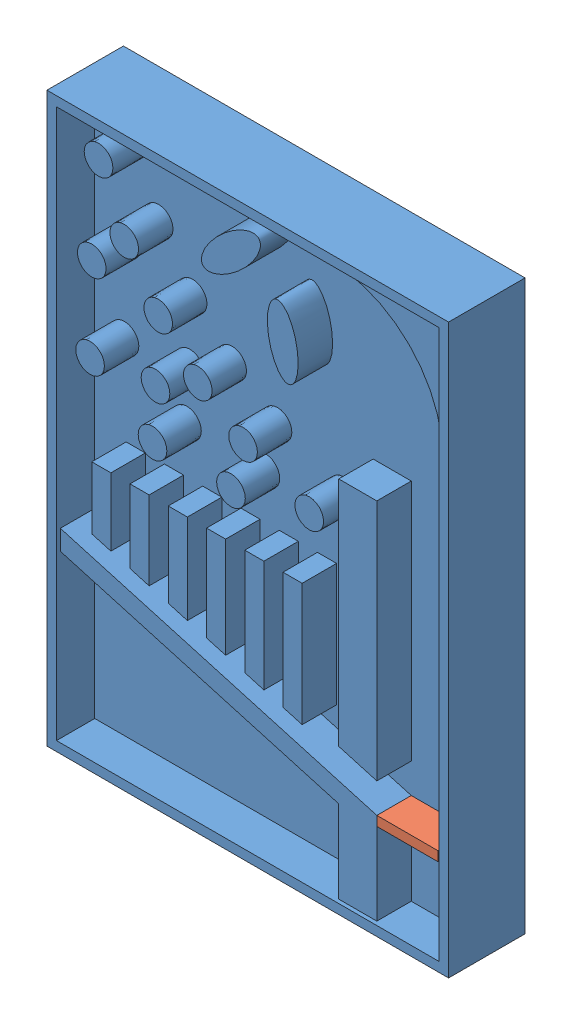
SolidWorks assembly w16, configuration 預設. Lengths in mm.
Overall size (210 297 40).
2 component instances, 2 part files, 3 mates.
Components (placement in the parent):
- 彈珠檯1-1: 彈珠檯1 [預設] at (-14.0331 -0.8378 297) size (210 297 40)
- 彈珠檯2-1: 彈珠檯2 [預設] at (67.4536 -96.4638 286) x (1 0 0) z (0 -1 0) size (32 18 5)
Mates (geometry in assembly coordinates):
- 重合/共線/共點1: coincident anti-aligned: plane of 彈珠檯1-1 through (-14.0331 -0.8378 277) normal (0 0 1); plane of 彈珠檯2-1 through (51.4536 -101.4638 277) normal (0 0 -1)
- 重合/共線/共點2: coincident aligned: line of 彈珠檯1-1 through (51.4536 -96.4638 295) axis (0 0 -1); line of 彈珠檯2-1 through (51.4536 -96.4638 295) axis (0 0 -1)
- 平行1: parallel anti-aligned: plane of 彈珠檯1-1 through (85.9669 -144.3378 277) normal (-1 0 0); plane of 彈珠檯2-1 through (83.4536 -101.4638 295) normal (1 0 0)
